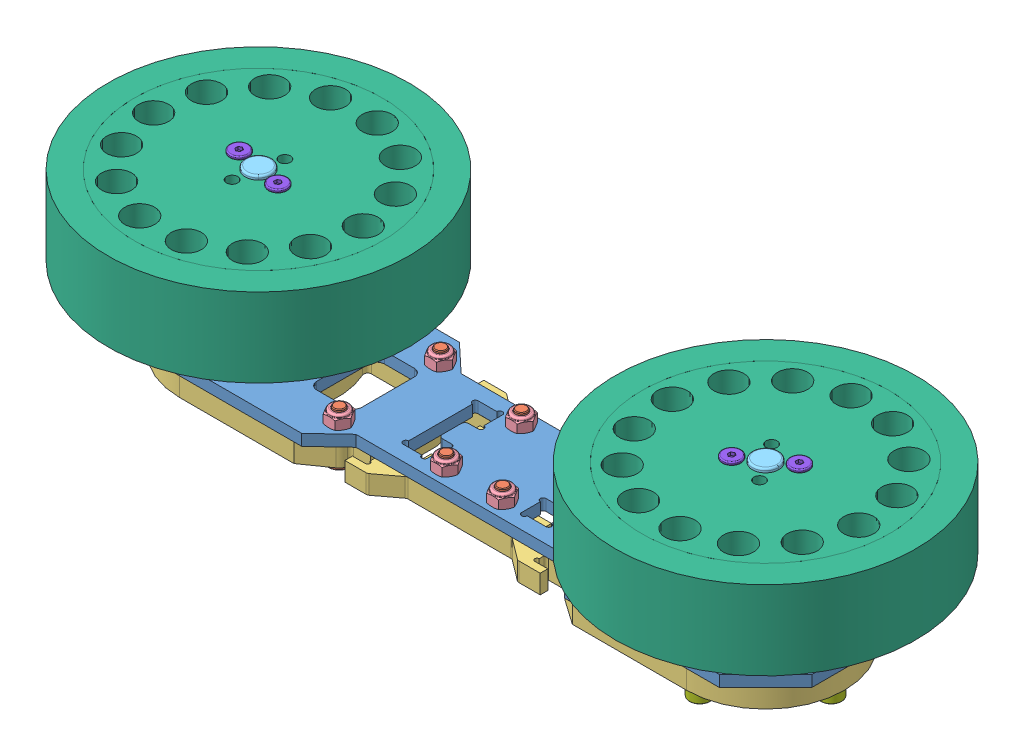
SolidWorks assembly 单侧摩擦轮装配, configuration 默认. Lengths in mm.
Overall size (237.39 46.1 111.1).
34 component instances, 8 part files, 38 mates.
Components (placement in the parent):
- 摩擦轮电机固定板_3mm-1: 摩擦轮电机固定板_3mm [默认] at origin size (177 3 42)
- M3×12扁头螺丝-3: M3×12扁头螺丝 [默认] at (-7.5 -7 10) x (1 0 0) z (0 -1 0) size (6 6 13)
- M3×12扁头螺丝-4: M3×12扁头螺丝 [默认] at (-32.5 -7 13.5) x (0.172866 0 0.984945) z (0 -1 0) size (6 6 13)
- 摩擦轮电机安装板加强板_5mm-1: 摩擦轮电机安装板加强板_5mm [默认] at (0 -4 0) x (0 0 -1) z (0 -1 0) size (42 177 5)
- M3防松-1: M3防松 [默认] at (-32.5 2.9 13.5) size (6.24 3.5 5.4)
- M3防松-2: M3防松 [默认] at (-7.5 2.9 10) size (6.24 3.5 5.4)
- M3×12扁头螺丝-5: M3×12扁头螺丝 [默认] at (-32.5 -7 -13.5) x (-0.172866 0 0.984945) z (0 -1 0) size (6 6 13)
- M3防松-3: M3防松 [默认] at (-7.5 2.9 -10) size (6.24 3.5 5.4)
- M3×12扁头螺丝-6: M3×12扁头螺丝 [默认] at (-7.5 -7 -10) x (-1 0 0) z (0 -1 0) size (6 6 13)
- M3防松-4: M3防松 [默认] at (-32.5 2.9 -13.5) size (6.24 3.5 5.4)
- M3×12扁头螺丝-7: M3×12扁头螺丝 [默认] at (32.5 -7 13.5) x (0.172866 0 -0.984945) z (0 -1 0) size (6 6 13)
- M3防松-5: M3防松 [默认] at (7.5 2.9 10) x (-1 0 0) z (0 0 -1) size (6.24 3.5 5.4)
- M3×12扁头螺丝-8: M3×12扁头螺丝 [默认] at (7.5 -7 10) x (1 0 0) z (0 -1 0) size (6 6 13)
- M3防松-6: M3防松 [默认] at (32.5 2.9 13.5) x (-1 0 0) z (0 0 -1) size (6.24 3.5 5.4)
- M3×12扁头螺丝-9: M3×12扁头螺丝 [默认] at (32.5 -7 -13.5) x (-0.172866 0 -0.984945) z (0 -1 0) size (6 6 13)
- M3防松-7: M3防松 [默认] at (7.5 2.9 -10) x (-1 0 0) z (0 0 -1) size (6.24 3.5 5.4)
- M3×12扁头螺丝-10: M3×12扁头螺丝 [默认] at (7.5 -7 -10) x (-1 0 0) z (0 -1 0) size (6 6 13)
- M3防松-8: M3防松 [默认] at (32.5 2.9 -13.5) x (-1 0 0) z (0 0 -1) size (6.24 3.5 5.4)
- YTRM3508-1: YTRM3508 [默认] at (-49.9139 51.941 -5.259) x (0.378508 0 0.925598) z (0 -1 0) size (42 42 43.4)
- YTRM3508-2: YTRM3508 [默认] at (58.7834 51.941 16.154) x (-0.922142 0 -0.386852) z (0 -1 0) size (42 42 43.4)
- 摩擦轮半径40-1: 摩擦轮半径40 [默认] at (-67.5 25.1 0) x (0.981973 0 0.189023) z (-0.189023 0 0.981973) size (80 21 80)
- 摩擦轮半径40-2: 摩擦轮半径40 [默认] at (67.5 25.1 0) x (0.828019 0 -0.5607) z (0.5607 0 0.828019) size (80 21 80)
- GB／T70．1-2000内六角圆柱头螺钉M3×12-1: GB／T70．1-2000内六角圆柱头螺钉M3×12 [默认] at (85 -9.5 0) x (0 1 0) z (0.11393 0 0.993489) size (15 5.5 5.5)
- GB／T70．1-2000内六角圆柱头螺钉M3×12-2: GB／T70．1-2000内六角圆柱头螺钉M3×12 [默认] at (-79.8744 -9.5 12.3744) x (0 1 0) z (0.276798 0 0.960928) size (15 5.5 5.5)
- GB／T70．1-2000内六角圆柱头螺钉M3×12-5: GB／T70．1-2000内六角圆柱头螺钉M3×12 [默认] at (67.5 -9.5 17.5) x (0 1 0) z (-0.993489 0 0.11393) size (15 5.5 5.5)
- GB／T70．1-2000内六角圆柱头螺钉M3×12-6: GB／T70．1-2000内六角圆柱头螺钉M3×12 [默认] at (50 -9.5 0) x (0 1 0) z (-0.11393 0 -0.993489) size (15 5.5 5.5)
- GB／T70．1-2000内六角圆柱头螺钉M3×12-7: GB／T70．1-2000内六角圆柱头螺钉M3×12 [默认] at (67.5 -9.5 -17.5) x (0 1 0) z (0.993489 0 -0.11393) size (15 5.5 5.5)
- GB／T70．1-2000内六角圆柱头螺钉M3×12-20: GB／T70．1-2000内六角圆柱头螺钉M3×12 [默认] at (-79.8744 -9.5 -12.3744) x (0 1 0) z (-0.960928 0 0.276798) size (15 5.5 5.5)
- GB／T70．1-2000内六角圆柱头螺钉M3×12-21: GB／T70．1-2000内六角圆柱头螺钉M3×12 [默认] at (-55.1256 -9.5 -12.3744) x (0 1 0) z (-0.276798 0 -0.960928) size (15 5.5 5.5)
- GB／T70．1-2000内六角圆柱头螺钉M3×12-22: GB／T70．1-2000内六角圆柱头螺钉M3×12 [默认] at (-55.1256 -9.5 12.3744) x (0 1 0) z (0.960928 0 -0.276798) size (15 5.5 5.5)
- M2.5×8扁头螺丝-1: M2.5×8扁头螺丝 [默认] at (72.8821 36.05 -3.6446) x (-0.837169 0 -0.546944) z (0 1 0) size (5 5 8.9)
- M2.5×8扁头螺丝-2: M2.5×8扁头螺丝 [默认] at (62.1179 36.05 3.6446) x (-0.837169 0 -0.546944) z (0 1 0) size (5 5 8.9)
- M2.5×8扁头螺丝-3: M2.5×8扁头螺丝 [默认] at (-61.1172 36.05 1.2286) x (-0.837169 0 -0.546944) z (0 1 0) size (5 5 8.9)
- M2.5×8扁头螺丝-4: M2.5×8扁头螺丝 [默认] at (-73.8828 36.05 -1.2286) x (-0.837169 0 -0.546944) z (0 1 0) size (5 5 8.9)
Mates (geometry in assembly coordinates):
- 重合1: coincident aligned: plane of 摩擦轮电机固定板_3mm-1 through (0 0 0) normal (0 0 1)
- 重合2: coincident aligned: plane of 摩擦轮电机固定板_3mm-1 through (0 0 0) normal (0 1 0)
- 重合3: coincident aligned: plane of 摩擦轮电机固定板_3mm-1 through (0 0 0) normal (1 0 0)
- 同心1: concentric anti-aligned: cylinder of 摩擦轮电机固定板_3mm-1 through (-32.5 -1.5 13.5) axis (0 1 0) radius 1.55; cylinder of M3×12扁头螺丝-4 through (-32.5 5.5 13.5) axis (0 -1 0) radius 1.5
- 同心2: concentric anti-aligned: cylinder of 摩擦轮电机固定板_3mm-1 through (-7.5 -1.5 10) axis (0 1 0) radius 1.55; cylinder of M3×12扁头螺丝-3 through (-7.5 5.5 10) axis (0 -1 0) radius 1.5
- 同心3: concentric anti-aligned: cylinder of M3×12扁头螺丝-4 through (-32.5 5.5 13.5) axis (0 -1 0) radius 1.5; cylinder of 摩擦轮电机安装板加强板_5mm-1 through (-32.5 -6.5 13.5) axis (0 1 0) radius 1.55
- 同心4: concentric anti-aligned: cylinder of M3×12扁头螺丝-3 through (-7.5 5.5 10) axis (0 -1 0) radius 1.5; cylinder of 摩擦轮电机安装板加强板_5mm-1 through (-7.5 -6.5 10) axis (0 1 0) radius 1.55
- 重合4: coincident anti-aligned: plane of 摩擦轮电机固定板_3mm-1 through (0 -1.5 0) normal (0 -1 0); plane of 摩擦轮电机安装板加强板_5mm-1 through (67.5 -1.5 0) normal (0 1 0)
- 重合5: coincident anti-aligned: plane of M3×12扁头螺丝-4 through (-32.5 -6.5 13.5) normal (0 1 0); plane of 摩擦轮电机安装板加强板_5mm-1 through (67.5 -6.5 0) normal (0 -1 0)
- 重合6: coincident anti-aligned: plane of M3×12扁头螺丝-3 through (-7.5 -6.5 10) normal (0 1 0); plane of 摩擦轮电机安装板加强板_5mm-1 through (67.5 -6.5 0) normal (0 -1 0)
- 同心5: concentric anti-aligned: cylinder of M3×12扁头螺丝-4 through (-32.5 5.5 13.5) axis (0 -1 0) radius 1.5; cylinder of M3防松-1 through (-32.5 1.5 13.5) axis (0 1 0) radius 1.5
- 重合7: coincident anti-aligned: plane of 摩擦轮电机固定板_3mm-1 through (0 1.5 0) normal (0 1 0); plane of M3防松-1 through (-32.5 1.5 13.5) normal (0 -1 0)
- 同心6: concentric anti-aligned: cylinder of M3×12扁头螺丝-3 through (-7.5 5.5 10) axis (0 -1 0) radius 1.5; cylinder of M3防松-2 through (-7.5 1.5 10) axis (0 1 0) radius 1.5
- 重合8: coincident anti-aligned: plane of 摩擦轮电机固定板_3mm-1 through (0 1.5 0) normal (0 1 0); plane of M3防松-2 through (-7.5 1.5 10) normal (0 -1 0)
- 同心7: concentric aligned: cylinder of 摩擦轮电机固定板_3mm-1 through (50 1.5 0) axis (0 -1 0) radius 1.55; cylinder of YTRM3508-2 through (50 1.5 0) axis (0 -1 0) radius 1.5
- 同心8: concentric anti-aligned: cylinder of 摩擦轮电机固定板_3mm-1 through (67.5 1.5 0) axis (0 -1 0) radius 13.4; cylinder of YTRM3508-2 through (67.5 -0.5 0) axis (0 1 0) radius 13.4
- 重合9: coincident anti-aligned: plane of 摩擦轮电机固定板_3mm-1 through (0 1.5 0) normal (0 1 0); plane of YTRM3508-2 through (67.5 1.5 0) normal (0 -1 0)
- 同心9: concentric aligned: cylinder of 摩擦轮电机固定板_3mm-1 through (-55.1256 1.5 12.3744) axis (0 -1 0) radius 1.55; cylinder of YTRM3508-1 through (-55.1256 1.5 12.3744) axis (0 -1 0) radius 1.5
- 同心10: concentric anti-aligned: cylinder of 摩擦轮电机固定板_3mm-1 through (-67.5 1.5 0) axis (0 -1 0) radius 13.4; cylinder of YTRM3508-1 through (-67.5 -0.5 0) axis (0 1 0) radius 13.4
- 重合10: coincident anti-aligned: plane of 摩擦轮电机固定板_3mm-1 through (0 1.5 0) normal (0 1 0); plane of YTRM3508-1 through (-67.5 1.5 0) normal (0 -1 0)
- 同心11: concentric aligned: cylinder of YTRM3508-1 through (-67.5 3.5 0) axis (0 -1 0) radius 21; cylinder of 摩擦轮半径40-1 through (-67.5 35.6 0) axis (0 -1 0) radius 21
- 同心12: concentric aligned: cylinder of YTRM3508-1 through (-61.1172 31.6 1.2286) axis (0 1 0) radius 1.25; cylinder of 摩擦轮半径40-1 through (-61.1172 -44.797 1.2286) axis (0 1 0) radius 1.5
- 重合11: coincident anti-aligned: plane of YTRM3508-1 through (-67.5 31.6 0) normal (0 1 0); plane of 摩擦轮半径40-1 through (-67.5 31.6 0) normal (0 -1 0)
- 同心13: concentric aligned: cylinder of YTRM3508-2 through (72.8821 31.6 -3.6446) axis (0 1 0) radius 1.25; cylinder of 摩擦轮半径40-2 through (72.8821 -44.797 -3.6446) axis (0 1 0) radius 1.5
- 同心14: concentric aligned: cylinder of YTRM3508-2 through (67.5 3.5 0) axis (0 -1 0) radius 21; cylinder of 摩擦轮半径40-2 through (67.5 35.6 0) axis (0 -1 0) radius 21
- 重合12: coincident anti-aligned: plane of YTRM3508-2 through (67.5 31.6 0) normal (0 1 0); plane of 摩擦轮半径40-2 through (67.5 31.6 0) normal (0 -1 0)
- 同心15: concentric anti-aligned: cylinder of 摩擦轮电机安装板加强板_5mm-1 through (-79.8744 -6.5 12.3744) axis (0 1 0) radius 1.55; cylinder of GB／T70．1-2000内六角圆柱头螺钉M3×12-2 through (-79.8744 -9.5 12.3744) axis (0 -1 0) radius 1.5
- 重合13: coincident anti-aligned: plane of 摩擦轮电机安装板加强板_5mm-1 through (67.5 -6.5 0) normal (0 -1 0); plane of GB／T70．1-2000内六角圆柱头螺钉M3×12-2 through (-82.5169 -6.5 13.1356) normal (0 1 0)
- 同心16: concentric anti-aligned: cylinder of 摩擦轮电机安装板加强板_5mm-1 through (85 -6.5 0) axis (0 1 0) radius 1.55; cylinder of GB／T70．1-2000内六角圆柱头螺钉M3×12-1 through (85 -9.5 0) axis (0 -1 0) radius 1.5
- 重合14: coincident anti-aligned: plane of 摩擦轮电机安装板加强板_5mm-1 through (67.5 -6.5 0) normal (0 -1 0); plane of GB／T70．1-2000内六角圆柱头螺钉M3×12-1 through (82.2679 -6.5 0.3133) normal (0 1 0)
- 同心18: concentric: cylinder of YTRM3508-1 through (-73.8828 31.6 -1.2286) axis (0 1 0) radius 1.25; cylinder of M2.5×8扁头螺丝-4 through (-73.4674 35.6 -2.1588) axis (0 1 0) radius 1.25
- 同心19: concentric: cylinder of YTRM3508-1 through (-61.1172 31.6 1.2286) axis (0 1 0) radius 1.25; cylinder of M2.5×8扁头螺丝-3 through (-61.4253 35.6 -0.0251) axis (0 1 0) radius 1.25
- 重合15: coincident anti-aligned: plane of 摩擦轮半径40-1 through (-67.5 35.6 0) normal (0 1 0); plane of M2.5×8扁头螺丝-4 through (-73.4674 43.6 -2.1588) normal (0 -1 0)
- 重合16: coincident anti-aligned: plane of 摩擦轮半径40-1 through (-67.5 35.6 0) normal (0 1 0); plane of M2.5×8扁头螺丝-3 through (-61.4253 43.6 -0.0251) normal (0 -1 0)
- 同心20: concentric: cylinder of YTRM3508-2 through (62.1179 31.6 3.6446) axis (0 1 0) radius 1.25; cylinder of M2.5×8扁头螺丝-2 through (61.3915 35.0269 2.1166) axis (0 1 0) radius 1.25
- 重合17: coincident anti-aligned: plane of 摩擦轮半径40-2 through (67.5 35.6 0) normal (0 1 0); plane of M2.5×8扁头螺丝-2 through (61.3915 43.0269 2.1166) normal (0 -1 0)
- 同心21: concentric: cylinder of YTRM3508-2 through (72.8821 31.6 -3.6446) axis (0 1 0) radius 1.25; cylinder of M2.5×8扁头螺丝-1 through (72.8707 35.6 -3.7174) axis (0 1 0) radius 1.25
- 重合18: coincident anti-aligned: plane of 摩擦轮半径40-2 through (67.5 35.6 0) normal (0 1 0); plane of M2.5×8扁头螺丝-1 through (72.8707 43.6 -3.7174) normal (0 -1 0)
